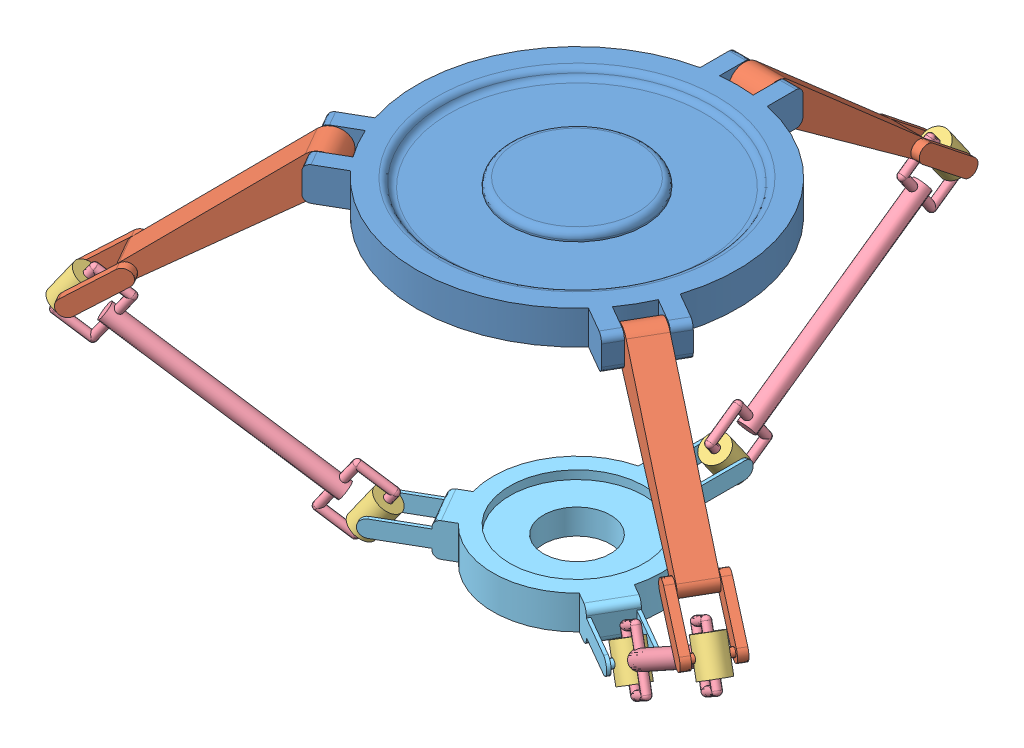
SolidWorks assembly delta_robot_urdf, configuration Default. Lengths in mm.
Overall size (1033.61 521.94 896.76).
14 component instances, 5 part files, 32 mates.
Components (placement in the parent):
- base_link-1: base_link [Default] at (178.2662 344.2207 399.4996) size (546.23 50 525.25)
- link_1-1: link_1 [Default] at (414.899 369.2207 536.1196) x (0.678001 -0.622163 0.391444) z (0.538809 0.782888 0.311081) size (387.5 75 50)
- link_1-2: link_1 [Default] at (-58.3665 369.2207 536.1196) x (-0.678001 -0.622163 0.391444) z (-0.538809 0.782888 0.311081) size (387.5 75 50)
- link_1-3: link_1 [Default] at (178.2662 369.2207 126.2596) x (0 -0.622163 -0.782888) z (0 0.782888 -0.622163) size (387.5 75 50)
- link_2-4: link_2 [Default] at (652.1993 151.4637 673.125) x (0.5 0 -0.866025) z (0.708519 0.575038 0.409063) size (40 50 40)
- link_2-5: link_2 [Default] at (-295.6668 151.4637 673.125) x (0.5 0 0.866025) z (0.708519 -0.575038 -0.409063) size (40 50 40)
- link_2-6: link_2 [Default] at (178.2662 151.4637 -147.7511) x (1 0 0) z (0 -0.575038 0.818127) size (40 50 40)
- link_3-2: link_3 [Default] at (652.1993 151.4637 673.125) x (-0.708519 -0.575038 -0.409063) z (0.5 0 -0.866025) size (412 87 25)
- link_3-3: link_3 [Default] at (-12.2593 -78.5514 509.4996) x (-0.708519 0.575038 0.409063) z (0.5 0 0.866025) size (412 87 25)
- link_3-4: link_3 [Default] at (178.2662 -78.5514 179.4996) x (0 0.575038 -0.818127) z (1 0 0) size (412 87 25)
- link_2-7: link_2 [Default] at (-12.2593 -78.5514 509.4996) x (0.5 0 0.866025) z (0.708519 -0.575038 -0.409063) size (40 50 40)
- link_2-8: link_2 [Default] at (178.2662 -78.5514 179.4996) x (1 0 0) z (0 -0.575038 0.818127) size (40 50 40)
- link_2-9: link_2 [Default] at (368.7918 -78.5514 509.4996) x (-0.5 0 0.866025) z (-0.708519 -0.575038 -0.409063) size (40 50 40)
- link_4-2: link_4 [Default] at (178.2662 -103.5514 399.4996) size (432.7 50 374.73)
Mates (geometry in assembly coordinates):
- Concentric1: concentric anti-aligned: cylinder of base_link-1 through (432.899 369.2207 504.9427) axis (-0.5 0 0.866025) radius 6; cylinder of link_1-1 through (402.899 369.2207 556.9042) axis (0.5 0 -0.866025) radius 6.25
- Distance1: distance = 1 mm anti-aligned: plane of base_link-1 through (438.8835 394.2207 521.0995) normal (-0.5 0 0.866025); plane of link_1-1 through (609.9592 201.2367 621.0249) normal (0.5 0 -0.866025)
- Concentric2: concentric anti-aligned: cylinder of base_link-1 through (142.2662 369.2207 126.2596) axis (1 0 0) radius 6; cylinder of link_1-3 through (202.2662 369.2207 126.2596) axis (-1 0 0) radius 6.25
- Distance2: distance = 1 mm anti-aligned: plane of link_1-3 through (202.2662 201.2367 -85.1201) normal (1 0 0); plane of base_link-1 through (203.2662 394.2207 112.9985) normal (-1 0 0)
- Concentric3: concentric anti-aligned: cylinder of base_link-1 through (-40.3665 369.2207 567.2965) axis (-0.5 0 -0.866025) radius 6; cylinder of link_1-2 through (-70.3665 369.2207 515.335) axis (0.5 0 0.866025) radius 6.25
- Distance3: distance = 1 mm anti-aligned: plane of base_link-1 through (-57.351 394.2207 564.4008) normal (-0.5 0 -0.866025); plane of link_1-2 through (-229.4267 201.2367 662.5941) normal (0.5 0 0.866025)
- Concentric7: concentric anti-aligned: cylinder of link_1-1 through (637.1993 151.4637 699.1057) axis (0.5 0 -0.866025) radius 6; cylinder of link_2-4 through (672.1993 151.4637 638.484) axis (-0.5 0 0.866025) radius 6.25
- Distance11: distance = 25 mm anti-aligned: plane of link_2-4 through (652.1993 151.4637 673.125) normal (0.5 0 -0.866025); plane of link_1-1 through (610.4592 201.2367 620.1588) normal (-0.5 0 0.866025)
- Concentric8: concentric anti-aligned: cylinder of link_1-2 through (-310.6668 151.4637 647.1442) axis (0.5 0 0.866025) radius 6; cylinder of link_2-5 through (-275.6668 151.4637 707.766) axis (-0.5 0 -0.866025) radius 6.25
- Distance12: distance = 25 mm aligned: plane of link_2-5 through (-295.6668 151.4637 673.125) normal (0.5 0 0.866025); plane of link_1-2 through (-253.9267 201.2367 620.1588) normal (0.5 0 0.866025)
- Concentric9: concentric aligned: cylinder of link_1-3 through (208.2662 151.4637 -147.7511) axis (-1 0 0) radius 6; cylinder of link_2-6 through (218.2662 151.4637 -147.7511) axis (-1 0 0) radius 6.25
- Distance13: distance = 25 mm aligned: plane of link_2-6 through (178.2662 151.4637 -147.7511) normal (1 0 0); plane of link_1-3 through (153.2662 201.2367 -85.1201) normal (1 0 0)
- Concentric10: concentric anti-aligned: cylinder of link_2-4 through (645.9743 161.6903 669.531) axis (-0.497997 0.818127 -0.287519) radius 6.25; cylinder of link_3-2 through (633.5244 182.1435 662.343) axis (0.497997 -0.818127 0.287519) radius 6
- Coincident14: coincident anti-aligned: plane of link_2-4 through (645.9743 161.6903 669.531) normal (-0.497997 0.818127 -0.287519); plane of link_3-2 through (645.9743 161.6903 669.531) normal (0.497997 -0.818127 0.287519)
- Concentric11: concentric anti-aligned: cylinder of link_2-5 through (-301.8917 141.2371 676.719) axis (-0.497997 -0.818127 0.287519) radius 6.25; cylinder of link_3-3 through (-314.3417 120.784 683.9069) axis (0.497997 0.818127 -0.287519) radius 6
- Coincident15: coincident anti-aligned: plane of link_2-5 through (-301.8917 141.2371 676.719) normal (-0.497997 -0.818127 0.287519); plane of link_3-3 through (-301.8917 141.2371 676.719) normal (0.497997 0.818127 -0.287519)
- Concentric12: concentric anti-aligned: cylinder of link_2-6 through (178.2662 161.6903 -140.5631) axis (0 0.818127 0.575038) radius 6.25; cylinder of link_3-4 through (178.2662 182.1435 -126.1872) axis (0 -0.818127 -0.575038) radius 6
- Coincident16: coincident anti-aligned: plane of link_2-6 through (178.2662 161.6903 -140.5631) normal (0 0.818127 0.575038); plane of link_3-4 through (178.2662 161.6903 -140.5631) normal (0 -0.818127 -0.575038)
- Concentric13: concentric aligned: cylinder of link_3-3 through (6.4156 -47.8717 498.7177) axis (-0.497997 -0.818127 0.287519) radius 6; cylinder of link_2-7 through (-18.4843 -88.778 513.0936) axis (-0.497997 -0.818127 0.287519) radius 6.25
- Coincident17: coincident anti-aligned: plane of link_3-3 through (-18.4843 -88.778 513.0936) normal (0.497997 0.818127 -0.287519); plane of link_2-7 through (-18.4843 -88.778 513.0936) normal (-0.497997 -0.818127 0.287519)
- Concentric14: concentric anti-aligned: cylinder of link_3-2 through (350.1169 -47.8717 498.7177) axis (0.497997 -0.818127 0.287519) radius 6; cylinder of link_2-9 through (362.5669 -68.3248 505.9056) axis (-0.497997 0.818127 -0.287519) radius 6.25
- Coincident18: coincident anti-aligned: plane of link_3-2 through (362.5669 -68.3248 505.9056) normal (0.497997 -0.818127 0.287519); plane of link_2-9 through (362.5669 -68.3248 505.9056) normal (-0.497997 0.818127 -0.287519)
- Concentric15: concentric anti-aligned: cylinder of link_3-4 through (178.2662 -47.8717 201.0635) axis (0 -0.818127 -0.575038) radius 6; cylinder of link_2-8 through (178.2662 -68.3248 186.6876) axis (0 0.818127 0.575038) radius 6.25
- Coincident19: coincident anti-aligned: plane of link_3-4 through (178.2662 -68.3248 186.6876) normal (0 -0.818127 -0.575038); plane of link_2-8 through (178.2662 -68.3248 186.6876) normal (0 0.818127 0.575038)
- Concentric16: concentric aligned: cylinder of link_2-7 through (7.7407 -78.5514 544.1406) axis (-0.5 0 -0.866025) radius 6.25; cylinder of link_4-2 through (0.7407 -78.5514 532.0163) axis (-0.5 0 -0.866025) radius 6
- Distance14: distance = 25 mm aligned: plane of link_2-7 through (-12.2593 -78.5514 509.4996) normal (0.5 0 0.866025); plane of link_4-2 through (35.8624 -78.5514 452.849) normal (0.5 0 0.866025)
- Concentric17: concentric anti-aligned: cylinder of link_2-9 through (348.7918 -78.5514 544.1406) axis (0.5 0 -0.866025) radius 6.25; cylinder of link_4-2 through (381.7918 -78.5514 486.983) axis (-0.5 0 0.866025) radius 6
- Distance16: distance = 25 mm aligned: plane of link_2-9 through (368.7918 -78.5514 509.4996) normal (-0.5 0 0.866025); plane of link_4-2 through (320.6701 -78.5514 452.849) normal (-0.5 0 0.866025)
- Concentric18: concentric anti-aligned: cylinder of link_2-8 through (218.2662 -78.5514 179.4996) axis (-1 0 0) radius 6.25; cylinder of link_4-2 through (152.2662 -78.5514 179.4996) axis (1 0 0) radius 6
- Distance17: distance = 25 mm aligned: plane of link_2-8 through (178.2662 -78.5514 179.4996) normal (1 0 0); plane of link_4-2 through (153.2662 -78.5514 249.4996) normal (1 0 0)
- Concentric19: concentric anti-aligned: cylinder of base_link-1 through (178.2662 394.2207 399.4996) axis (0 -1 0) radius 238.7509; cylinder of link_4-2 through (178.2662 -103.5514 399.4996) axis (0 1 0) radius 50
- Angle4: planar angle = 2.617994 rad anti-aligned: plane of base_link-1 through (178.2662 344.2207 399.4996) normal (0 -1 0); plane of link_1-1 through (576.4995 187.0507 657.1325) normal (-0.520802 -0.798971 -0.300685)
